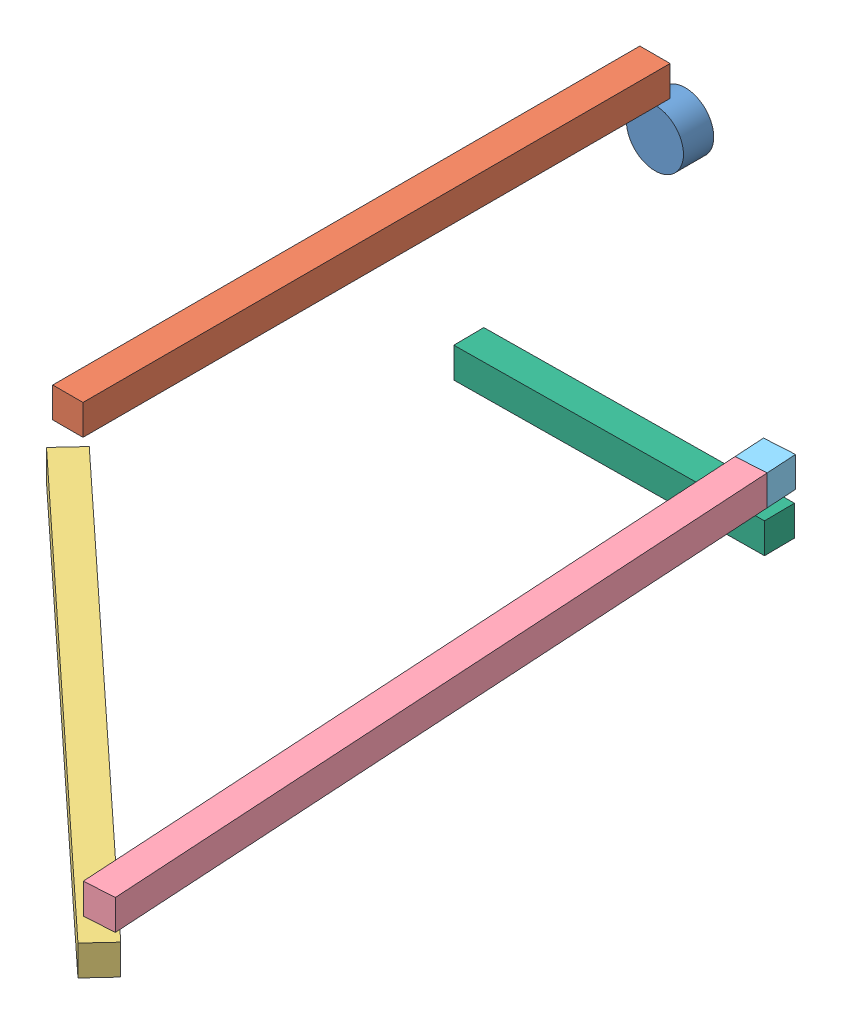
SolidWorks assembly Assem1, configuration Default. Lengths in mm.
Overall size (275.81 260.81 347.69).
6 component instances, 6 part files, 21 mates.
Components (placement in the parent):
- Base-2: Base [Default] at origin size (18.82 18.82 10)
- Vertical-1: Vertical [Default] at (0 18.82 204) x (0 1 0) z (0 0 -1) size (23.82 10 196.8)
- Arm 1-1: Arm 1 [Default] at (0 3.57 204) x (0.680721 0 -0.732543) z (0.732543 0 0.680721) size (10 20.25 205.7)
- Arm 2-1: Arm 2 [Default] at (133.2048 18.82 111.4398) x (0.998188 0 -0.060177) z (0.060177 0 0.998188) size (24 27.21 229.6)
- Pivot-1: Pivot [Default] at (133.2048 18.82 111.4398) x (0 1 0) z (-0.060177 0 -0.998188) size (24 24 16.77)
- Pointer-1: Pointer [Default] at (31.0061 0 102.5219) x (0.010472 0 0.999945) z (0.999945 0 -0.010472) size (10 23.82 101.6)
Mates (geometry in assembly coordinates):
- Coincident75: coincident: point of Base-2; point of Vertical-1
- Coincident92: coincident aligned: line of Base-2 through (0 0 0) axis (0 1 0); line of assembly
- Coincident76: coincident anti-aligned: plane of Base-2 through (0 0 10) normal (0 0 1); plane of Vertical-1 through (0 18.82 10) normal (0 0 -1)
- Coincident79: coincident: point of Vertical-1; point of Arm 1-1
- Coincident81: coincident: point of Base-2; point of assembly
- Coincident82: coincident anti-aligned: line of Base-2 through (9.41 0 0) axis (-1 0 0); line of assembly
- Coincident83: coincident aligned: line of Vertical-1 through (0 13.82 204) axis (0 1 0); line of Arm 1-1 through (0 3.57 204) axis (0 1 0)
- Coincident84: coincident: point of Arm 1-1; point of Arm 2-1
- Coincident85: coincident aligned: line of Arm 1-1 through (147.0214 3.57 340.6207) axis (0 1 0); line of Arm 2-1 through (147.0214 18.82 340.6207) axis (0 1 0)
- Coincident86: coincident: point of Arm 2-1; point of Pivot-1
- Coincident87: coincident anti-aligned: plane of Arm 2-1 through (133.2048 18.82 111.4398) normal (-0.060177 0 -0.998188); plane of Pivot-1 through (133.2048 18.82 111.4398) normal (0.060177 0 0.998188)
- Coincident88: coincident: point of Pivot-1; point of Pointer-1
- Coincident89: coincident anti-aligned: line of Pivot-1 through (132.603 23.82 101.4579) axis (0 -1 0); line of Pointer-1 through (132.603 0 101.4579) axis (0 1 0)
- Parallel24: parallel aligned: plane of Base-2 through (0 0 0) normal (0 0 -1); plane of Pointer-1 through (147.9843 -5 94.98) normal (0 0 -1)
- E0 (Base Angle): planar angle = 3.141593 rad aligned: line of Vertical-1 through (0 13.82 10) axis (0 -1 0); line of assembly
- E1: planar angle = 0.748746 rad aligned: line of Arm 1-1 through (0 -1.43 204) axis (0.732543 0 0.680721); line of Vertical-1 through (0 13.82 204) axis (1 0 0)
- E2: planar angle = 2.379756 rad aligned: line of Arm 2-1 through (147.0214 13.82 340.6207) axis (-0.060177 0 -0.998188); line of Arm 1-1 through (147.0214 -1.43 340.6207) axis (0.732543 0 0.680721)
- E3 (Wrist Angle): planar angle = 0 rad aligned: line of Arm 2-1 through (133.2048 18.82 111.4398) axis (0 -1 0); line of Pivot-1 through (133.2048 18.82 111.4398) axis (0 -1 0)
- E4: planar angle = 1.521054 rad aligned: line of Pivot-1 through (132.3021 13.82 96.467) axis (0.060177 0 0.998188); line of Pointer-1 through (122.6036 5 101.5626) axis (0.999945 0 -0.010472)
- Coincident117: coincident: unknown of ?
- Angle13: planar angle = 0 rad aligned: line of Arm 1-1 through (148.4308 -1.43 339.0881) axis (0.739565 0 0.673085); line of Arm 2-1 through (148.4308 13.82 339.0881) axis (-0.06385 0 -0.99796)
